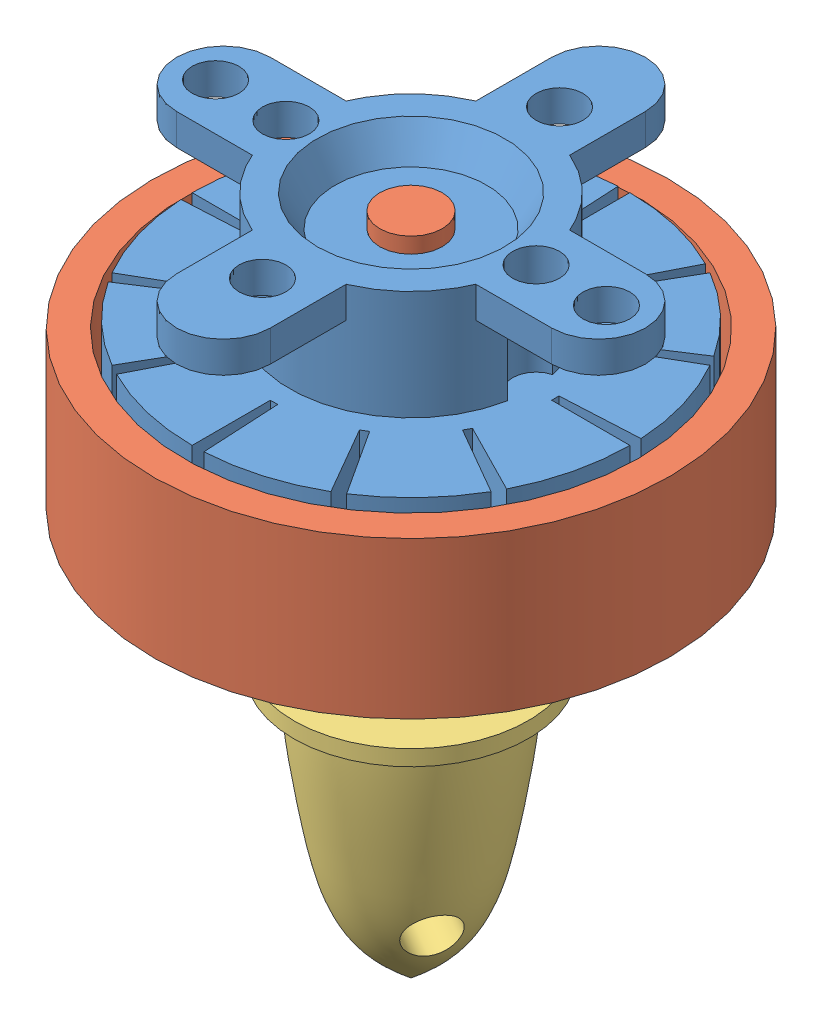
SolidWorks assembly Assem2, configuration Default. Lengths in mm.
Overall size (33.28 43.5 33.28).
3 component instances, 3 part files, 4 mates.
Components (placement in the parent):
- Part2-1: Part2 [Default] at (10.0456 18.1164 21.964) size (30 15 30)
- Part3-1: Part3 [Default] at (10.0456 12.6164 21.964) x (-0.008659 0 -0.999963) z (-0.999963 0 0.008659) size (33 35.5 33)
- Part4-1: Part4 [Default] at (10.0456 -6.3836 21.964) x (-0.863787 0 -0.503858) z (-0.503858 0 0.863787) size (15 18 15)
Mates (geometry in assembly coordinates):
- Concentric1: concentric anti-aligned: cylinder of Part2-1 through (10.0456 5.1164 21.964) axis (0 1 0) radius 1.5; cylinder of Part3-1 through (10.0456 18.1164 21.964) axis (0 -1 0) radius 1.5
- Coincident1: coincident anti-aligned: plane of Part2-1 through (14.0456 18.1164 21.964) normal (0 1 0); plane of Part3-1 through (10.0456 18.1164 21.964) normal (0 -1 0)
- Concentric2: concentric aligned: cylinder of Part3-1 through (10.0456 12.6164 21.964) axis (0 1 0) radius 3; cylinder of Part4-1 through (10.0456 -17.3836 21.964) axis (0 1 0) radius 3.5
- Distance1: distance = 4 mm anti-aligned: plane of Part3-1 through (9.9936 -1.3836 15.9642) normal (0 -1 0); plane of Part4-1 through (10.0456 -5.3836 21.964) normal (0 1 0)
